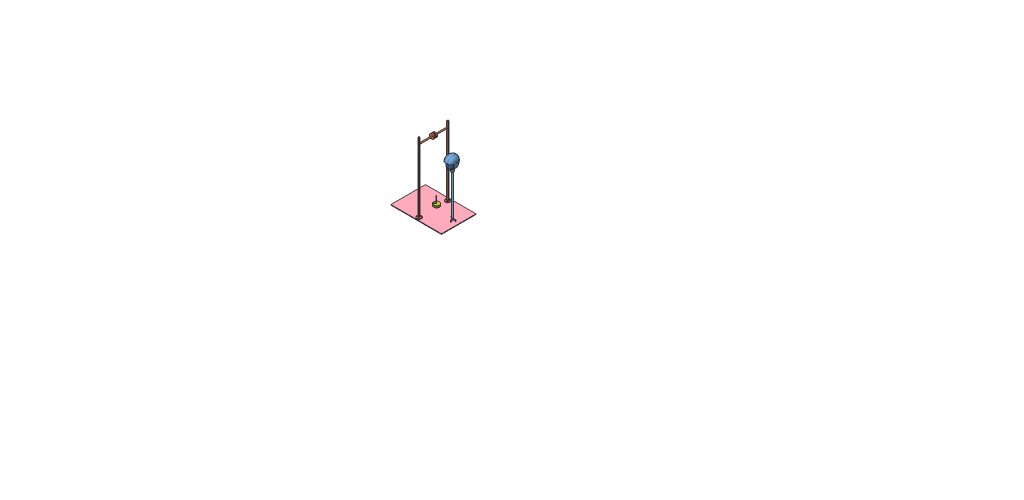
SolidWorks assembly project assembly, configuration Default. Lengths in mm.
Overall size (13933.14 4148.49 6637.65).
21 component instances, 8 part files, 5 mates.
Components (placement in the parent):
- Helmet-1: Helmet [Default] at (-203.4747 -1603.6334 84.492) size (232.75 323.76 255.82)
- project-1: project [Default] at (-679.0837 -1202.4081 -1297.4831) size (1117.6 1546.86 762)
  - project main setup-1: project main setup [Default] at (63.6047 132.3867 1379.0583) size (101.6 1534.16 736.6)
  - Project -nut boltu-1: Project -nut boltu [Default] at (82.6547 119.6867 1028.5627) size (19.05 27.94 19.05)
  - Project -nut boltu-2: Project -nut boltu [Default] at (82.6547 119.6867 1729.5539) size (19.05 27.94 19.05)
  - Project -nut boltu-3: Project -nut boltu [Default] at (25.5047 119.6867 1061.5583) x (0.994551 0 -0.10425) z (0.10425 0 0.994551) size (19.05 27.94 19.05)
  - Project -nut boltu-4: Project -nut boltu [Default] at (82.6547 119.6867 1094.5539) x (0.444899 0 0.895581) z (-0.895581 0 0.444899) size (19.05 27.94 19.05)
  - Project -nut boltu-5: Project -nut boltu [Default] at (25.5047 119.6867 1696.5583) x (-0.068077 0 0.99768) z (-0.99768 0 -0.068077) size (19.05 27.94 19.05)
  - Project -nut boltu-6: Project -nut boltu [Default] at (82.6547 119.6867 1663.5627) size (19.05 27.94 19.05)
  - Project_base-1: Project_base [Default] at (63.6047 132.3867 1379.0583) size (1117.6 12.7 762)
- stand maniquin-1: stand maniquin [Default] at (-203.4747 -139.8234 74.2782) x (-0.518481 0 0.855089) z (0 -1 0) size (90.52 137.38 930)
- weight plate and umbrella assem-1: weight plate and umbrella assem [Default] at (-362.9243 -841.7145 110.2716) x (-0.792021 0.010631 -0.610401) z (-0.610346 0.008193 0.792092) size (141.43 171.97 141.23)
  - umbrella-1: umbrella [Default] at (189.9035 74.7407 90.4662) size (120 171.97 120)
  - weight umbrella-1: weight umbrella [Default] at (182.4991 132.1144 85.3731) x (0.993128 0 -0.117032) z (0 1 0) size (127 126.76 10)
  - weight umbrella-2: weight umbrella [Default] at (182.5077 122.1144 85.3691) x (0.993324 0 -0.115355) z (0 1 0) size (127 126.76 10)
  - weight umbrella-3: weight umbrella [Default] at (182.4775 112.1144 85.3833) x (0.992623 0 -0.121238) z (0 1 0) size (127 126.76 10)
  - weight umbrella-4: weight umbrella [Default] at (182.4859 102.1144 85.3793) x (0.992822 0 -0.119599) z (0 1 0) size (127 126.76 10)
- ajaira-1: ajaira [Default] at (-3219.8766 1039.4641 2214.5823) size (2 2 1)
- ajaira-2: ajaira [Default] at (-4289.4499 2647.7537 4957.0981) size (2 2 1)
- ajaira-3: ajaira [Default] at (9641.6866 -1498.7405 -1679.5502) size (2 2 1)
- ajaira-6: ajaira [Default] at (-211.0924 -605.8839 131.5326) size (2 2 1)
Mates (geometry in assembly coordinates):
- Parallel1: parallel anti-aligned: plane of Helmet-1 through (-203.4747 -139.8234 74.2782) normal (0 -1 0); plane of stand maniquin-1 through (-203.4747 -139.8234 74.2782) normal (0 1 0)
- Parallel2: parallel anti-aligned: plane of Helmet-1 through (-203.4747 -139.8234 74.2782) normal (0 -1 0); plane of stand maniquin-1 through (-203.4747 -139.8234 74.2782) normal (0 1 0)
- Concentric1: concentric anti-aligned: cylinder of Helmet-1 through (-203.4747 -56.8234 74.2782) axis (0 -1 0) radius 32.8125; cylinder of stand maniquin-1 through (-203.4747 -1039.8234 74.2782) axis (0 1 0) radius 15
- Coincident4: coincident anti-aligned: plane of Helmet-1 through (-203.4747 -139.8234 74.2782) normal (0 -1 0); plane of stand maniquin-1 through (-203.4747 -139.8234 74.2782) normal (0 1 0)
- Perpendicular1: perpendicular: cylinder of project-1/project main setup-1 through (-615.479 337.1385 386.3752) axis (0 0 1) radius 25.4; cylinder of weight plate and umbrella assem-1/umbrella-1 through (-566.4975 -982.1092 69.0787) axis (0.013422 0.99991 0) radius 5.0176
